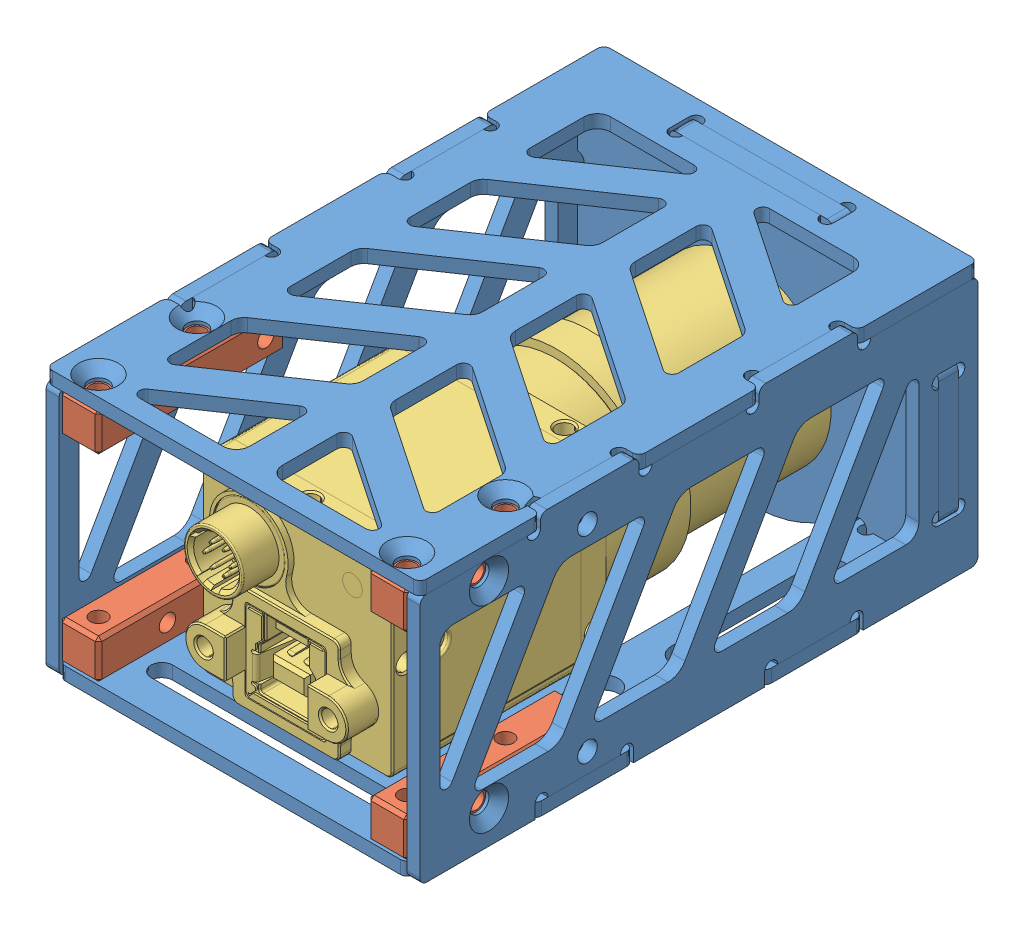
SolidWorks assembly 相机模块, configuration 默认. Lengths in mm.
Overall size (57 43.5 85).
6 component instances, 3 part files, 7 mates.
Components (placement in the parent):
- 相机顶部安装板-1: 相机顶部安装板 [默认] at origin size (57 43.5 85)
- 铝条直角连接双孔-通用型-1: 铝条直角连接双孔-通用型 [默认] at (-23.5 5 -25.5) x (0 0 -1) z (-1 0 0) size (28.5 6 6)
- 铝条直角连接双孔-通用型-4: 铝条直角连接双孔-通用型 [默认] at (23.5 5 -25.5) x (0 0 -1) z (-1 0 0) size (28.5 6 6)
- 铝条直角连接双孔-通用型-5: 铝条直角连接双孔-通用型 [默认] at (-23.5 35 -25.5) x (0 0 -1) z (-1 0 0) size (28.5 6 6)
- 铝条直角连接双孔-通用型-6: 铝条直角连接双孔-通用型 [默认] at (23.5 35 -25.5) x (0 0 -1) z (-1 0 0) size (28.5 6 6)
- SUA50G-T-V100；MV-LD-6-4M-G-1: SUA50G-T-V100；MV-LD-6-4M-G [默认] at (-102.8074 79.8912 -9.8) x (1 0 0) z (0 0 -1) size (31 31 74.25)
Mates (geometry in assembly coordinates):
- 同心5: concentric aligned: cylinder of 相机顶部安装板-1 through (-23.5 2 -18) axis (0 -1 0) radius 1.5; cylinder of 铝条直角连接双孔-通用型-1 through (-23.5 2 -18) axis (0 -1 0) radius 1.25
- 同心6: concentric anti-aligned: cylinder of 相机顶部安装板-1 through (-28.5 5 -25.5) axis (1 0 0) radius 1.5; cylinder of 铝条直角连接双孔-通用型-1 through (-26.5 5 -25.5) axis (-1 0 0) radius 1.25
- 同心7: concentric aligned: cylinder of 相机顶部安装板-1 through (-23.5 40 -3) axis (0 -1 0) radius 1.5; cylinder of 铝条直角连接双孔-通用型-5 through (-23.5 32 -3) axis (0 -1 0) radius 1.25
- 同心8: concentric anti-aligned: cylinder of 相机顶部安装板-1 through (-28.5 35 -10.5) axis (1 0 0) radius 1.5; cylinder of 铝条直角连接双孔-通用型-5 through (-26.5 35 -10.5) axis (-1 0 0) radius 1.25
- 重合1: coincident anti-aligned: plane of 相机顶部安装板-1 through (0 2 0) normal (0 1 0); plane of SUA50G-T-V100；MV-LD-6-4M-G-1 through (14.5 2 -38.5) normal (0 -1 0)
- 同心9: concentric anti-aligned: cylinder of 相机顶部安装板-1 through (-10 2 -40.5) axis (0 -1 0) radius 1.5; cylinder of SUA50G-T-V100；MV-LD-6-4M-G-1 through (-10 2 -40.5) axis (0 1 0) radius 1.25
- 同心10: concentric anti-aligned: cylinder of 相机顶部安装板-1 through (10 2 -40.5) axis (0 -1 0) radius 1.5; cylinder of SUA50G-T-V100；MV-LD-6-4M-G-1 through (10 2 -40.5) axis (0 1 0) radius 1.25
